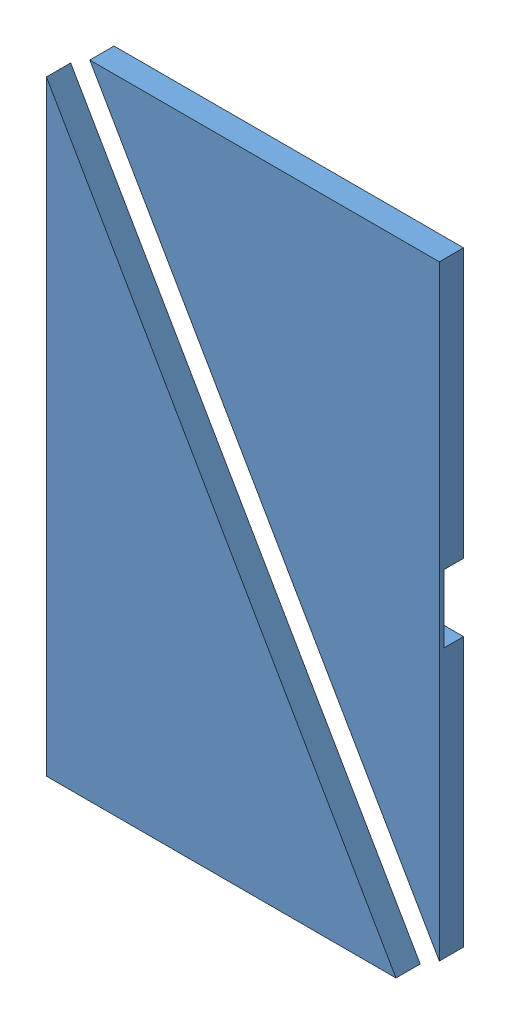
SolidWorks assembly Canard_Halves_1_Machineing_Asm, configuration Default. Lengths in mm.
Overall size (43.74 69.85 5.08).
2 component instances, 1 part files, 3 mates.
Components (placement in the parent):
- Canard_Half-1: Canard_Half [Default] at (-24.0742 -15.7606 23.4112) size (36.65 63.5 2.54)
- Canard_Half-2: Canard_Half [Default] at (17.1241 51.5494 23.4112) x (-1 0 0) z (0 0 1) size (36.65 63.5 2.54)
Mates (geometry in assembly coordinates):
- Distance1: distance = 5.842 mm anti-aligned: plane of Canard_Half-1 through (-24.0742 47.7394 25.9512) normal (0.866082 0.499902 0); plane of Canard_Half-2 through (17.1241 -11.9506 25.9512) normal (-0.866082 -0.499902 0)
- Coincident2: coincident aligned: plane of Canard_Half-1 through (-24.0742 -15.7606 23.4112) normal (0 0 -1); plane of Canard_Half-2 through (17.1241 51.5494 23.4112) normal (0 0 -1)
- Distance2: distance = 3.81 mm: plane of Canard_Half-1 through (-24.0742 -15.7606 25.9512) normal (0 -1 0); moEndPointRef_w of Canard_Half-2
